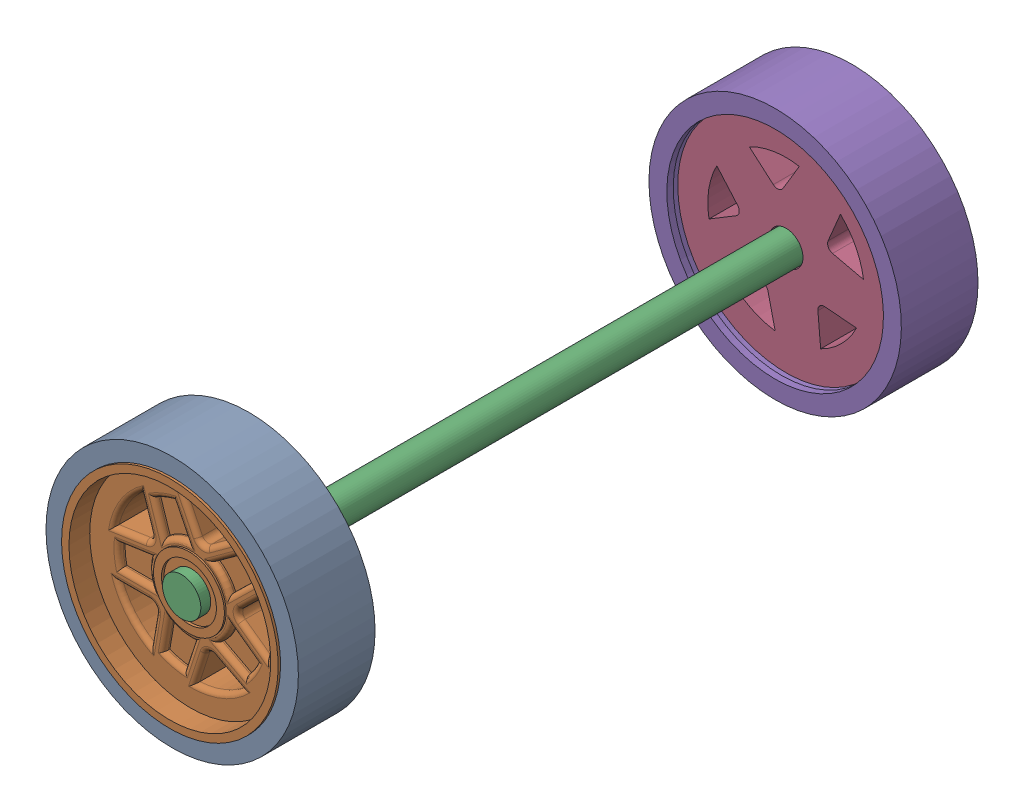
SolidWorks assembly TIRE WHEEL N AXLE ASSY, configuration Default. Lengths in mm.
Overall size (13.63 13.63 27.21).
5 component instances, 3 part files, 4 mates.
Components (placement in the parent):
- tire-1: tire [Default] at (0.352 0.7391 1.8521) size (10.03 10.03 3.05)
- star wheel-1: star wheel [Default] at (0.352 0.7391 2.5977) x (0.925941 0.377669 0) z (0 0 1) size (9.25 9.25 2.72)
- axle truck-1: axle truck [Default] at (0.352 0.7391 0.4595) x (0 0 -1) z (0.873288 0.487205 0) size (26.42 1.52 1.52)
- star wheel-2: star wheel [Default] at (0.352 0.7391 -27.9544) x (-0.891945 0.452144 0) z (0 0 -1) size (9.25 9.25 2.72)
- tire-2: tire [Default] at (0.352 0.7391 -22.1172) x (0.875409 -0.483383 0) z (0 0 1) size (10.03 10.03 3.05)
Mates (geometry in assembly coordinates):
- Concentric1: concentric aligned: cylinder of tire-1 through (0.352 0.7391 -1.9579) axis (0 0 1) radius 4.826; cylinder of star wheel-1 through (0.352 0.7391 -1.7891) axis (0 0 1) radius 4.6228
- Concentric2: concentric aligned: cylinder of star wheel-1 through (0.352 0.7391 -1.7891) axis (0 0 1) radius 0.6731; cylinder of axle truck-1 through (0.352 0.7391 -25.4485) axis (0 0 1) radius 0.635
- Concentric3: concentric anti-aligned: cylinder of axle truck-1 through (0.352 0.7391 -25.4485) axis (0 0 1) radius 0.635; cylinder of star wheel-2 through (0.352 0.7391 -23.5675) axis (0 0 -1) radius 0.6731
- Concentric4: concentric anti-aligned: cylinder of star wheel-2 through (0.352 0.7391 -23.5675) axis (0 0 -1) radius 4.6228; cylinder of tire-2 through (0.352 0.7391 -25.9272) axis (0 0 1) radius 4.826
